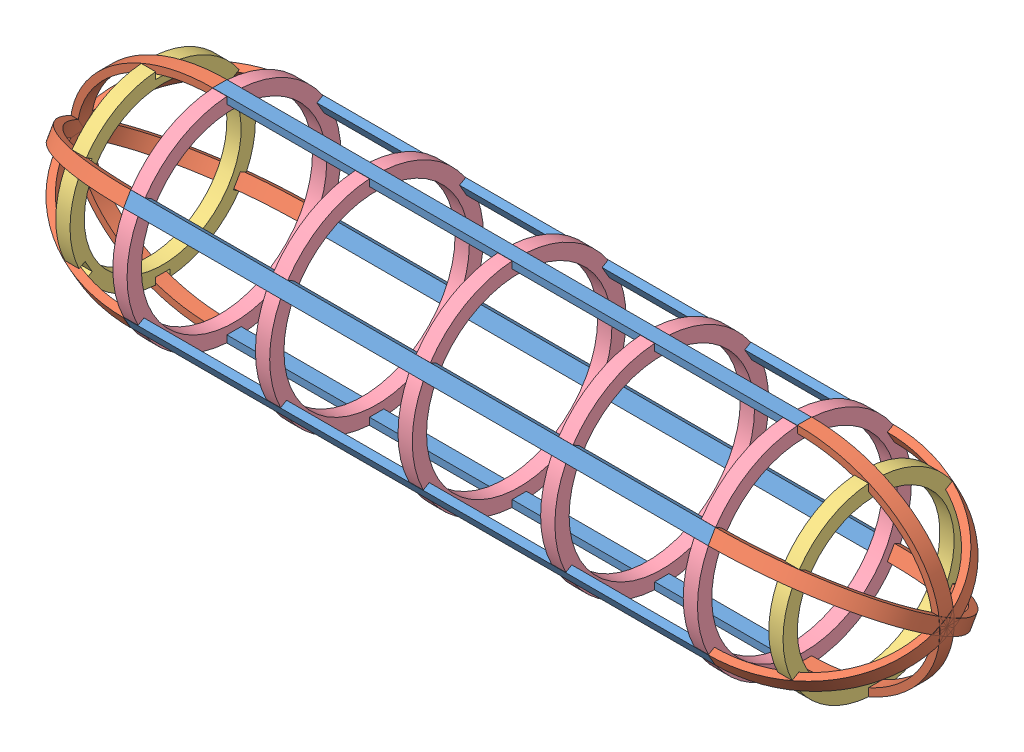
SolidWorks assembly zeppeling_assembly, configuration Predeterminado. Lengths in mm.
Overall size (610 204.74 204.61).
27 component instances, 4 part files, 59 mates.
Components (placement in the parent):
- beam-1: beam [Predeterminado] at (-235.111 37.3276 206.0693) x (1 0 0) z (0 -0.5 -0.866025) size (410 10 5)
- beam-2: beam [Predeterminado] at (-235.111 70.4974 138.6174) x (1 0 0) z (0 -1 0) size (410 10 5)
- beam-3: beam [Predeterminado] at (-235.111 -74.5026 138.6174) x (1 0 0) z (0 -1 0) size (410 10 5)
- beam-4: beam [Predeterminado] at (-235.111 28.6673 76.1655) x (1 0 0) z (0 -0.5 0.866025) size (410 10 5)
- beam-5: beam [Predeterminado] at (-235.111 -35.1724 80.4956) x (1 0 0) z (0 -0.5 -0.866025) size (410 10 5)
- beam-6: beam [Predeterminado] at (-235.111 -43.8327 201.7391) x (1 0 0) z (0 -0.5 0.866025) size (410 10 5)
- front_back-1: front_back [Predeterminado] at (-226.6086 79.0399 208.9176) x (1 0 0) z (0 -0.866025 -0.5) size (100 150 134.9)
  - beam2-1: beam2 [Predeterminado] at (-8.5023 -14.6311 100) size (100 75 10)
  - circle_small-1: circle_small [Predeterminado] at (-58.5023 -14.7805 105) x (0 0 -1) z (1 0 0) size (130 129.61 10)
  - beam2-2: beam2 [Predeterminado] at (-8.5023 -14.6311 110) x (1 0 0) z (0 0 -1) size (100 75 10)
  - beam2-3: beam2 [Predeterminado] at (-8.5023 -19.1106 102.5) x (1 0 0) z (0 0.866025 0.5) size (100 75 10)
  - beam2-4: beam2 [Predeterminado] at (-8.5023 -10.4503 107.5) x (1 0 0) z (0 -0.866025 -0.5) size (100 75 10)
  - beam2-5: beam2 [Predeterminado] at (-8.5023 -10.4503 102.5) x (1 0 0) z (0 -0.866025 0.5) size (100 75 10)
  - beam2-6: beam2 [Predeterminado] at (-8.5023 -19.1106 107.5) x (1 0 0) z (0 0.866025 -0.5) size (100 75 10)
- front_back-2: front_back [Predeterminado] at (166.3867 10.2779 248.6174) x (-1 0 0) z (0 0 -1) size (100 150 134.9)
  - beam2-1: beam2 [Predeterminado] at (-8.5023 -14.6311 100) size (100 75 10)
  - circle_small-1: circle_small [Predeterminado] at (-58.5023 -14.7805 105) x (0 0 -1) z (1 0 0) size (130 129.61 10)
  - beam2-2: beam2 [Predeterminado] at (-8.5023 -14.6311 110) x (1 0 0) z (0 0 -1) size (100 75 10)
  - beam2-3: beam2 [Predeterminado] at (-8.5023 -19.1106 102.5) x (1 0 0) z (0 0.866025 0.5) size (100 75 10)
  - beam2-4: beam2 [Predeterminado] at (-8.5023 -10.4503 107.5) x (1 0 0) z (0 -0.866025 -0.5) size (100 75 10)
  - beam2-5: beam2 [Predeterminado] at (-8.5023 -10.4503 102.5) x (1 0 0) z (0 -0.866025 0.5) size (100 75 10)
  - beam2-6: beam2 [Predeterminado] at (-8.5023 -19.1106 107.5) x (1 0 0) z (0 0.866025 -0.5) size (100 75 10)
- central_circle-6: central_circle [Predeterminado] at (-235.111 -4.5026 143.6174) x (0 0 -1) z (1 0 0) size (150 149.67 10)
- central_circle-7: central_circle [Predeterminado] at (164.889 -4.5026 143.6174) x (0 0.866025 -0.5) z (1 0 0) size (150 149.67 10)
- central_circle-8: central_circle [Predeterminado] at (-125.111 -4.5026 143.6174) x (0 0 -1) z (-1 0 0) size (150 149.67 10)
- central_circle-9: central_circle [Predeterminado] at (-35.111 -4.5026 143.6174) x (0 0 -1) z (1 0 0) size (150 149.67 10)
- central_circle-10: central_circle [Predeterminado] at (64.889 -4.5026 143.6174) x (0 0 -1) z (1 0 0) size (150 149.67 10)
Mates (geometry in assembly coordinates):
- Distance1: distance = 90 mm anti-aligned: plane of circle_small-1 through (-35.111 4.3912 150) normal (-1 0 0); plane of circle_small-3 through (-125.111 4.3912 150) normal (1 0 0)
- Distance2: distance = 90 mm anti-aligned: plane of circle_small-1 through (-25.111 4.3912 150) normal (1 0 0); plane of circle_small-2 through (64.889 5.4797 150.2991) normal (-1 0 0)
- Distance5: distance = 90 mm anti-aligned: plane of circle_small-3 through (-135.111 4.3912 150) normal (-1 0 0); plane of circle_small-4 through (-225.111 4.3912 150) normal (1 0 0)
- Distance6: distance = 90 mm anti-aligned: plane of circle_small-2 through (74.889 5.4797 150.2991) normal (1 0 0); plane of circle_small-5 through (164.889 5.4797 150.2991) normal (-1 0 0)
- Concentric1: concentric aligned: circle of central_circle-3; circle of central_circle-4
- Concentric2: concentric aligned: circle of central_circle-2; circle of central_circle-5
- Coincident5: coincident anti-aligned: plane of circle_small-4 through (-235.111 30.0611 204.4615) normal (0 0.5 0.866025); plane of beam-1 through (-235.111 38.2359 203.8452) normal (0 -0.5 -0.866025)
- Coincident6: coincident anti-aligned: plane of circle_small-4 through (-235.111 38.7213 199.4615) normal (0 -0.866025 0.5); plane of beam-1 through (-235.111 38.2359 203.8452) normal (0 0.866025 -0.5)
- Coincident7: coincident aligned: plane of circle_small-4 through (-235.111 4.3912 150) normal (-1 0 0); plane of beam-1 through (-235.111 38.2359 203.8452) normal (-1 0 0)
- Coincident8: coincident anti-aligned: plane of circle_small-4 through (-235.111 -29.9389 199.4615) normal (0 -0.5 0.866025); plane of beam-6 through (-235.111 -40.4244 203.8452) normal (0 0.5 -0.866025)
- Coincident9: coincident anti-aligned: plane of circle_small-4 through (-235.111 -29.9389 199.4615) normal (0 0.866025 0.5); plane of beam-6 through (-235.111 -42.9244 208.1753) normal (0 -0.866025 -0.5)
- Coincident10: coincident aligned: plane of circle_small-4 through (-235.111 4.3912 150) normal (-1 0 0); plane of beam-6 through (-235.111 -42.9244 208.1753) normal (-1 0 0)
- Coincident11: coincident anti-aligned: plane of circle_small-4 through (-235.111 -55.6088 145) normal (0 -1 0); plane of beam-3 through (-235.111 -71.0943 140.7234) normal (0 1 0)
- Coincident12: coincident anti-aligned: plane of circle_small-4 through (-235.111 -55.6088 145) normal (0 0 1); plane of beam-3 through (-235.111 -76.0943 140.7234) normal (0 0 -1)
- Coincident13: coincident aligned: plane of circle_small-4 through (-235.111 4.3912 150) normal (-1 0 0); plane of beam-3 through (-235.111 -76.0943 140.7234) normal (-1 0 0)
- Coincident14: coincident anti-aligned: plane of circle_small-4 through (-235.111 38.7213 100.5385) normal (0 0.5 -0.866025); plane of beam-4 through (-235.111 29.5756 82.6016) normal (0 -0.5 0.866025)
- Coincident15: coincident anti-aligned: plane of circle_small-4 through (-235.111 30.0611 95.5385) normal (0 0.866025 0.5); plane of beam-4 through (-235.111 29.5756 82.6016) normal (0 -0.866025 -0.5)
- Coincident16: coincident aligned: plane of circle_small-4 through (-235.111 4.3912 150) normal (-1 0 0); plane of beam-4 through (-235.111 29.5756 82.6016) normal (-1 0 0)
- Coincident17: coincident anti-aligned: plane of circle_small-4 through (-235.111 64.3912 155) normal (0 1 0); plane of beam-2 through (-235.111 68.9057 140.7234) normal (0 -1 0)
- Coincident18: coincident aligned: plane of circle_small-4 through (-235.111 4.3912 150) normal (-1 0 0); plane of beam-2 through (-235.111 68.9057 140.7234) normal (-1 0 0)
- Coincident19: coincident: plane of circle_small-4 through (-235.111 64.3912 155) normal (0 0 -1); line of beam-2 through (-235.111 73.9057 150.7234) axis (1 0 0)
- Coincident20: coincident anti-aligned: plane of circle_small-4 through (-235.111 -21.2787 95.5385) normal (0 -0.5 -0.866025); plane of beam-5 through (-250.2677 -31.7641 82.6016) normal (0 0.5 0.866025)
- Coincident21: coincident anti-aligned: plane of circle_small-4 through (-235.111 -21.2787 95.5385) normal (0 -0.866025 0.5); plane of beam-5 through (-250.2677 -34.2641 78.2715) normal (0 0.866025 -0.5)
- Coincident22: coincident aligned: plane of circle_small-4 through (-235.111 4.3912 150) normal (-1 0 0); plane of beam-5 through (-250.2677 -34.2641 78.2715) normal (-1 0 0)
- Coincident23: coincident anti-aligned: plane of beam-1 through (-235.111 34.8276 201.7391) normal (-1 0 0); plane of front_back-1/beam2-3 through (-235.111 28.6673 211.0693) normal (1 0 0)
- Coincident24: coincident aligned: plane of beam-1 through (-235.111 26.1673 206.7391) normal (0 -0.866025 0.5); plane of front_back-1/beam2-3 through (-302.8216 15.6838 188.5812) normal (0 -0.866025 0.5)
- Coincident25: coincident anti-aligned: plane of circle_small-1 through (-35.111 30.0611 204.4615) normal (0 0.866025 -0.5); plane of beam-1 through (-235.111 29.5756 208.8452) normal (0 -0.866025 0.5)
- Coincident26: coincident anti-aligned: plane of circle_small-1 through (-35.111 30.0611 204.4615) normal (0 0.5 0.866025); plane of beam-1 through (-235.111 38.2359 203.8452) normal (0 -0.5 -0.866025)
- Coincident27: coincident anti-aligned: line of beam-1 through (-235.111 37.3276 206.0693) axis (0 -0.866025 0.5); line of front_back-1/beam2-3 through (-235.111 28.6673 211.0693) axis (0 0.866025 -0.5)
- Coincident28: coincident anti-aligned: plane of beam-2 through (-235.111 65.4974 138.6174) normal (0 -1 0); plane of central_circle-6 through (-235.111 65.4974 148.6174) normal (0 1 0)
- Coincident29: coincident anti-aligned: plane of beam-2 through (-235.111 65.4974 148.6174) normal (0 0 1); plane of central_circle-6 through (-235.111 65.4974 148.6174) normal (0 0 -1)
- Coincident30: coincident: line of beam-1 through (-235.111 37.3276 206.0693) axis (1 0 0); plane of central_circle-6 through (-235.111 34.8276 201.7391) normal (0 -0.866025 0.5)
- Coincident31: coincident anti-aligned: plane of beam-1 through (-235.111 34.8276 201.7391) normal (0 -0.5 -0.866025); plane of central_circle-6 through (-235.111 26.1673 206.7391) normal (0 0.5 0.866025)
- Coincident33: coincident anti-aligned: plane of beam-3 through (-235.111 -74.5026 138.6174) normal (0 1 0); plane of central_circle-6 through (-235.111 -74.5026 138.6174) normal (0 -1 0)
- Coincident34: coincident anti-aligned: plane of beam-3 through (-235.111 -79.5026 138.6174) normal (0 0 -1); plane of central_circle-6 through (-235.111 -74.5026 138.6174) normal (0 0 1)
- Coincident35: coincident anti-aligned: plane of beam-5 through (-235.111 -37.6724 76.1655) normal (0 0.866025 -0.5); plane of central_circle-6 through (-235.111 -35.1724 80.4956) normal (0 -0.866025 0.5)
- Coincident36: coincident anti-aligned: plane of beam-5 through (-235.111 -35.1724 80.4956) normal (0 0.5 0.866025); plane of central_circle-6 through (-235.111 -35.1724 80.4956) normal (0 -0.5 -0.866025)
- Coincident37: coincident anti-aligned: plane of beam-4 through (-235.111 34.8276 85.4956) normal (0 0.866025 0.5); plane of central_circle-6 through (-235.111 34.8276 85.4956) normal (0 -0.866025 -0.5)
- Coincident38: coincident anti-aligned: plane of beam-4 through (-235.111 26.1673 80.4956) normal (0 -0.5 0.866025); plane of central_circle-6 through (-235.111 34.8276 85.4956) normal (0 0.5 -0.866025)
- Coincident39: coincident anti-aligned: plane of beam-6 through (-235.111 -43.8327 201.7391) normal (0 0.5 -0.866025); plane of central_circle-6 through (-235.111 -43.8327 201.7391) normal (0 -0.5 0.866025)
- Coincident40: coincident anti-aligned: plane of beam-6 through (-235.111 -46.3327 206.0693) normal (0 -0.866025 -0.5); plane of central_circle-6 through (-235.111 -43.8327 201.7391) normal (0 0.866025 0.5)
- Coincident41: coincident: line of beam-3 through (-235.111 -79.5026 138.6174) axis (0 0 1); plane of central_circle-6 through (-235.111 -4.5026 143.6174) normal (-1 0 0)
- Coincident42: coincident: line of beam-6 through (-235.111 -46.3327 206.0693) axis (0 0.866025 0.5); plane of central_circle-6 through (-235.111 -4.5026 143.6174) normal (-1 0 0)
- Coincident43: coincident: line of front_back-1/beam2-3 through (-235.111 28.6673 211.0693) axis (0 0.866025 -0.5); plane of central_circle-6 through (-235.111 -4.5026 143.6174) normal (-1 0 0)
- Coincident44: coincident aligned: plane of beam-5 through (174.889 -37.6724 76.1655) normal (1 0 0); plane of central_circle-7 through (174.889 -4.5026 143.6174) normal (1 0 0)
- Coincident45: coincident anti-aligned: plane of beam-5 through (-235.111 -35.1724 80.4956) normal (0 0.5 0.866025); plane of central_circle-7 through (164.889 -35.1724 80.4956) normal (0 -0.5 -0.866025)
- Coincident47: coincident anti-aligned: plane of beam-5 through (-235.111 -46.3327 81.1655) normal (0 -0.866025 0.5); plane of central_circle-7 through (164.889 -43.8327 85.4956) normal (0 0.866025 -0.5)
- Coincident48: coincident anti-aligned: plane of front_back-2/beam2-5 through (174.889 28.6673 76.1655) normal (-1 0 0); plane of central_circle-7 through (174.889 -4.5026 143.6174) normal (1 0 0)
- Coincident49: coincident aligned: line of beam-4 through (174.889 28.6673 76.1655) axis (0 0.866025 0.5); line of front_back-2/beam2-5 through (174.889 28.6673 76.1655) axis (0 0.866025 0.5)
- Coincident50: coincident anti-aligned: line of front_back-2/beam2-5 through (174.889 28.6673 76.1655) axis (0 -0.5 0.866025); line of central_circle-7 through (174.889 26.1673 80.4956) axis (0 0.5 -0.866025)
- Coincident51: coincident anti-aligned: plane of beam-2 through (-235.111 65.4974 138.6174) normal (0 -1 0); plane of central_circle-8 through (-125.111 65.4974 138.6174) normal (0 1 0)
- Coincident52: coincident anti-aligned: plane of beam-2 through (-235.111 65.4974 148.6174) normal (0 0 1); plane of central_circle-8 through (-125.111 65.4974 148.6174) normal (0 0 -1)
- Distance7: distance = 90 mm anti-aligned: plane of central_circle-6 through (-225.111 -4.5026 143.6174) normal (1 0 0); plane of central_circle-8 through (-135.111 -4.5026 143.6174) normal (-1 0 0)
- Coincident54: coincident anti-aligned: plane of beam-2 through (-235.111 65.4974 138.6174) normal (0 -1 0); plane of central_circle-9 through (-35.111 65.4974 148.6174) normal (0 1 0)
- Coincident55: coincident anti-aligned: plane of beam-2 through (-235.111 65.4974 148.6174) normal (0 0 1); plane of central_circle-9 through (-35.111 65.4974 148.6174) normal (0 0 -1)
- Distance8: distance = 90 mm anti-aligned: plane of central_circle-9 through (-35.111 -4.5026 143.6174) normal (-1 0 0); plane of central_circle-8 through (-125.111 -4.5026 143.6174) normal (1 0 0)
- Coincident57: coincident anti-aligned: plane of beam-2 through (-235.111 65.4974 138.6174) normal (0 -1 0); plane of central_circle-10 through (64.889 65.4974 148.6174) normal (0 1 0)
- Coincident58: coincident anti-aligned: plane of beam-2 through (-235.111 65.4974 148.6174) normal (0 0 1); plane of central_circle-10 through (64.889 65.4974 148.6174) normal (0 0 -1)
- Distance9: distance = 90 mm anti-aligned: plane of central_circle-10 through (64.889 -4.5026 143.6174) normal (-1 0 0); plane of central_circle-9 through (-25.111 -4.5026 143.6174) normal (1 0 0)
